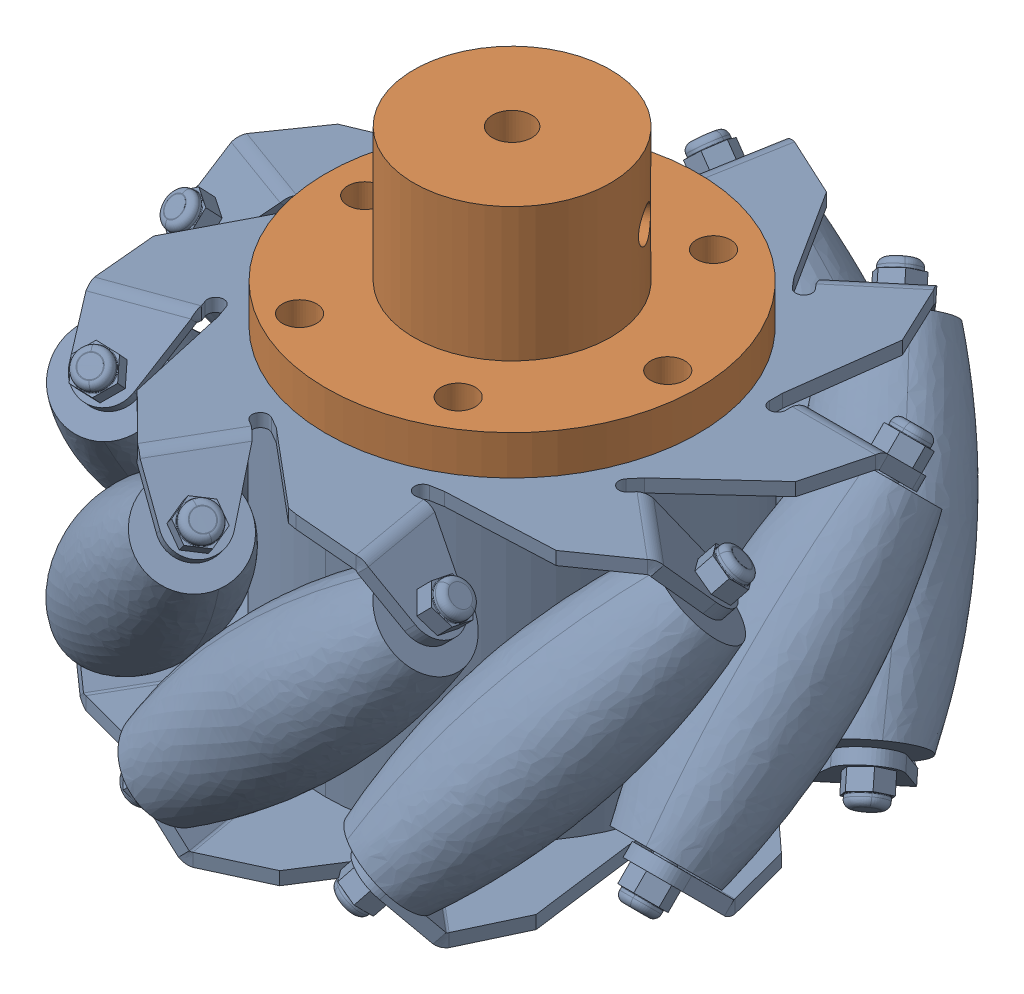
SolidWorks assembly 100mm_RF, configuration 默认. Lengths in mm.
Overall size (102.05 76.39 102.38).
2 component instances, 2 part files, 4 mates.
Components (placement in the parent):
- 100mm_RF-1: 100mm_RF [默认] at origin size (102.05 50.01 102.38)
- 6mm_TightCoupling-1: 6mm_TightCoupling [默认] at (0 47.9113 0) x (-0.5 0 -0.866025) z (0 1 0) size (56.8 56.8 26.4)
Mates (geometry in assembly coordinates):
- 同心3: concentric: cylinder of 100mm_RF-1 through (-11.875 -2.0707 20.5681) axis (0 1 0) radius 2.5; cylinder of 6mm_TightCoupling-1 through (-11.875 47.9113 20.5681) axis (0 1 0) radius 2.6
- 同心4: concentric: cylinder of 100mm_RF-1 through (-11.875 -2.0707 -20.5681) axis (0 1 0) radius 2.5; cylinder of 6mm_TightCoupling-1 through (-11.875 47.9113 -20.5681) axis (0 1 0) radius 2.6
- 同心5: concentric: cylinder of 100mm_RF-1 through (23.75 -2.0707 0) axis (0 1 0) radius 2.5; cylinder of 6mm_TightCoupling-1 through (23.75 47.9113 0) axis (0 1 0) radius 2.6
- 重合1: coincident anti-aligned: plane of 100mm_RF-1 through (0 47.9113 0) normal (0 1 0); plane of 6mm_TightCoupling-1 through (3.8049 47.9113 6.5902) normal (0 -1 0)
